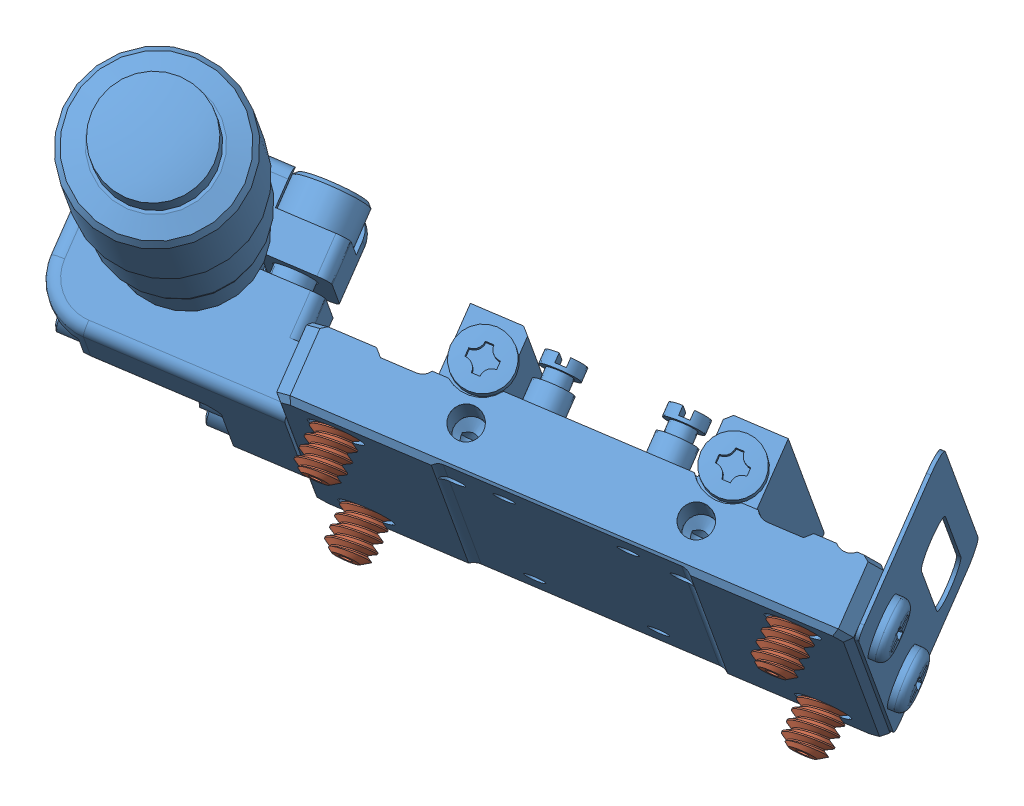
SolidWorks assembly Stage_122-0070_with_bolts, configuration Default. Lengths in mm.
Overall size (85.38 72.37 72.85).
6 component instances, 3 part files, 11 mates.
Components (placement in the parent):
- TSD-401SUU-C1B-S07-1: TSD-401SUU-C1B-S07 [Default] at (24.0193 -47.1553 -10.1213) x (0.873594 -0.248588 -0.418375) z (-0.156541 0.670463 -0.72524) size (59.6 67 15.55)
- TSD-401SUU-C1B-S08-1: TSD-401SUU-C1B-S08 [Default] at (21.602 -36.4527 -21.767) x (0.873594 -0.248588 -0.418375) z (-0.156541 0.670463 -0.72524) size (64.1 43.23 10.9) (hidden)
- 6-32_L=0.19inch-1: 6-32_L=0.19inch [93235A142] at (3.3467 -56.4939 -9.7939) x (0.986154 0.065421 -0.152379) z (0.156541 -0.670463 0.72524) size (5.74 5.74 8.58)
- 6-32_L=0.19inch-2: 6-32_L=0.19inch [93235A142] at (17.9768 -34.2988 7.5669) x (0.986154 0.065421 -0.152379) z (0.156541 -0.670463 0.72524) size (5.74 5.74 8.58)
- 6-32_L=0.19inch-3: 6-32_L=0.19inch [93235A142] at (45.7134 -42.1915 -5.7165) x (0.986154 0.065421 -0.152379) z (0.156541 -0.670463 0.72524) size (5.74 5.74 8.58)
- 6-32_L=0.19inch-4: 6-32_L=0.19inch [93235A142] at (31.0833 -64.3866 -23.0773) x (0.986154 0.065421 -0.152379) z (0.156541 -0.670463 0.72524) size (5.74 5.74 8.58)
Mates (geometry in assembly coordinates):
- Concentric1: concentric anti-aligned: circle of TSD-401SUU-C1B-S07-1; circle of 6-32_L=0.19inch-1
- Concentric2: concentric anti-aligned: circle of TSD-401SUU-C1B-S07-1; circle of 6-32_L=0.19inch-2
- Concentric3: concentric anti-aligned: circle of TSD-401SUU-C1B-S07-1; circle of 6-32_L=0.19inch-3
- Concentric4: concentric anti-aligned: circle of TSD-401SUU-C1B-S07-1; circle of 6-32_L=0.19inch-4
- Coincident1: coincident anti-aligned: plane of TSD-401SUU-C1B-S07-1 through (25.9142 -62.6868 -26.957) normal (-0.156541 0.670463 -0.72524); plane of 6-32_L=0.19inch-4 through (30.3377 -61.1935 -26.5313) normal (0.156541 -0.670463 0.72524)
- Coincident2: coincident anti-aligned: plane of TSD-401SUU-C1B-S07-1 through (40.5444 -40.4917 -9.5962) normal (-0.156541 0.670463 -0.72524); plane of 6-32_L=0.19inch-3 through (44.9679 -38.9984 -9.1704) normal (0.156541 -0.670463 0.72524)
- Coincident3: coincident anti-aligned: plane of TSD-401SUU-C1B-S07-1 through (12.8078 -32.599 3.6872) normal (-0.156541 0.670463 -0.72524); plane of 6-32_L=0.19inch-2 through (17.2313 -31.1057 4.113) normal (0.156541 -0.670463 0.72524)
- Coincident4: coincident anti-aligned: plane of TSD-401SUU-C1B-S07-1 through (-1.8224 -54.7941 -13.6736) normal (-0.156541 0.670463 -0.72524); plane of 6-32_L=0.19inch-1 through (2.6011 -53.3008 -13.2479) normal (0.156541 -0.670463 0.72524)
- Coincident6: coincident anti-aligned: plane of TSD-401SUU-C1B-S07-1 through (40.4535 -47.3334 -23.7428) normal (-0.873594 0.248588 0.418375); plane of TSD-401SUU-C1B-S08-1 through (40.6393 -48.1291 -22.8821) normal (0.873594 -0.248588 -0.418375)
- Coincident7: coincident aligned: plane of TSD-401SUU-C1B-S07-1 through (32.6484 -30.4119 -2.2223) normal (0.460792 0.699058 0.546798); plane of TSD-401SUU-C1B-S08-1 through (31.4974 -25.3823 -7.6825) normal (0.460792 0.699058 0.546798)
- Distance1: distance = 0.5 mm anti-aligned: plane of TSD-401SUU-C1B-S08-1 through (21.9378 -42.4319 -14.4058) normal (0.156541 -0.670463 0.72524); plane of TSD-401SUU-C1B-S07-1 through (29.0048 -44.7559 -17.3902) normal (-0.156541 0.670463 -0.72524)
